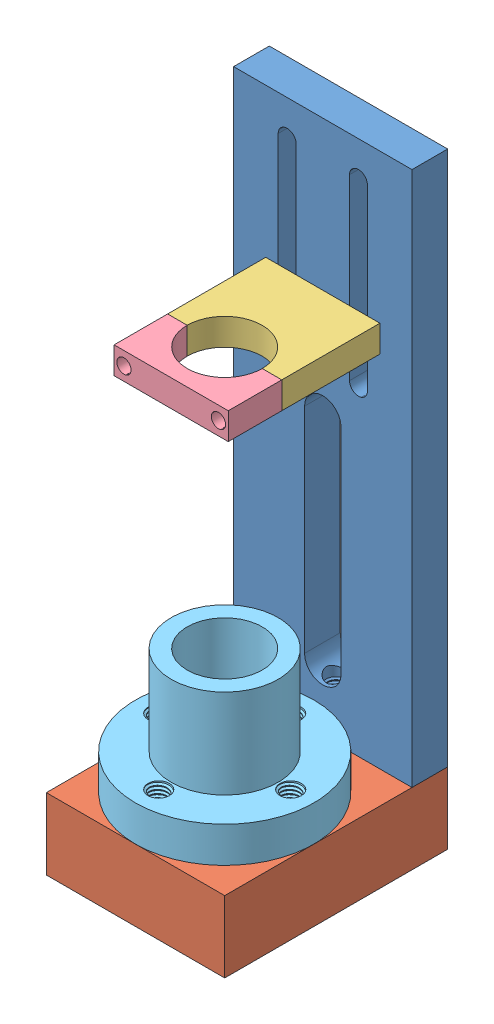
SolidWorks assembly Assemblage1, configuration Défaut. Lengths in mm.
Overall size (50 170 62.5).
12 component instances, 10 part files, 13 mates.
Components (placement in the parent):
- base support piston-1: base support piston [Défaut] at origin size (50 150 10)
- pièce 1 support piston-1: pièce 1 support piston [Défaut] at (0 -20 0) x (-1 0 0) z (0 1 0) size (50 62.5 20)
- petit support piston-1: petit support piston [Défaut] at (0 100.7052 10) x (-1 0 0) z (0 0 -1) size (32 7.5 27.61)
- petit support piston partie haute-1: petit support piston partie haute [Défaut] at (0 100.7052 52.5) size (32 7.5 15)
- Nez cylindrique-1: Nez cylindrique [Défaut] at (0 10 37.5) x (0 0 1) z (0 -1 0) size (50 50 35.87)
- Assemblage bloc piston-1: Assemblage bloc piston [Défaut] at (-12.2216 111.5 13.4244) x (-0.452651 0 -0.891688) z (-0.891688 0 0.452651) size (77.49 99 58.23) (hidden)
  - chambre 1-1: chambre 1 [Défaut] x (-1 0 0) z (0 0 -1) size (21 99 21)
  - chambre 2-1: chambre 2 [Défaut] at (-27 0 0) x (-0.809017 0 -0.587785) z (0.587785 0 -0.809017) size (27.63 99 21.5)
  - chambre 3-1: chambre 3 [Défaut] at (-54 0 0) x (-1 0 0) z (0 0 -1) size (21 99 21)
  - demi ton pfister perce 11.7 modèle 12.7x0.75 ht08-10-15-1: demi ton pfister perce 11.7 modèle 12.7x0.75 ht08-10-15 [Défaut] at (-27.7406 43.5 11.8226) x (-0.809017 0 -0.587785) z (0 1 0) size (32.9 21.49 12.7)
  - demi ton pour piston 2 perce 11.5 modèle 12,5 x 019-1: demi ton pour piston 2 perce 11.5 modèle 12,5 x 019 [Défaut] at (-33.5566 25 9.0244) x (0.4388 0.840129 0.318807) z (0.679678 -0.542387 0.493815) size (44 24 12.5)
  - demi ton pfister perce 11.7 modèle 12.7x0.75 ht08-10-15-2: demi ton pfister perce 11.7 modèle 12.7x0.75 ht08-10-15 [Défaut] at (-15.2501 47.9306 22.1336) x (-0.686085 0.529919 -0.49847) z (-0.428714 -0.848048 -0.311479) size (32.9 21.49 12.7)
Mates (geometry in assembly coordinates):
- Coïncidente1: coincident anti-aligned: plane of base support piston-1 through (-25 0 10) normal (0 -1 0); plane of pièce 1 support piston-1 through (0 0 0) normal (0 1 0)
- Coïncidente2: coincident aligned: plane of base support piston-1 through (0 0 0) normal (0 0 -1); plane of pièce 1 support piston-1 through (25 0 0) normal (0 0 -1)
- Coaxiale1: concentric aligned: circle of base support piston-1; circle of pièce 1 support piston-1
- Coïncidente8: coincident anti-aligned: plane of base support piston-1 through (0 0 10) normal (0 0 1); plane of petit support piston-1 through (16 108.2052 10) normal (0 0 -1)
- Distance3: distance = 9 mm: line of petit support piston-1 through (-16 108.2052 10) axis (0 -1 0); line of base support piston-1 through (-25 150 10) axis (0 -1 0)
- Coaxiale3: concentric anti-aligned: circle of petit support piston-1; circle of petit support piston partie haute-1
- Coaxiale4: concentric anti-aligned: circle of petit support piston-1; circle of petit support piston partie haute-1
- Coïncidente11: coincident anti-aligned: plane of petit support piston-1 through (-10.505 108.2052 37.5) normal (0 0 1); plane of petit support piston partie haute-1 through (-16 108.2052 37.5) normal (0 0 -1)
- Coaxiale5: concentric anti-aligned: circle of pièce 1 support piston-1; circle of Nez cylindrique-1
- Coaxiale6: concentric anti-aligned: circle of pièce 1 support piston-1; circle of Nez cylindrique-1
- Coïncidente12: coincident anti-aligned: plane of pièce 1 support piston-1 through (0 0 0) normal (0 1 0); plane of Nez cylindrique-1 through (0 0 37.5) normal (0 -1 0)
- Coaxiale8: concentric anti-aligned: cylinder of Nez cylindrique-1 through (0 35 37.5) axis (0 -1 0) radius 15; cylinder of Assemblage bloc piston-1/chambre 2-1 through (0 12.5 37.5) axis (0 1 0) radius 10.5
- Coïncidente14: coincident anti-aligned: plane of Nez cylindrique-1 through (0 12.5 37.5) normal (0 1 0); plane of Assemblage bloc piston-1/chambre 2-1 through (0 12.5 37.5) normal (0 -1 0)
